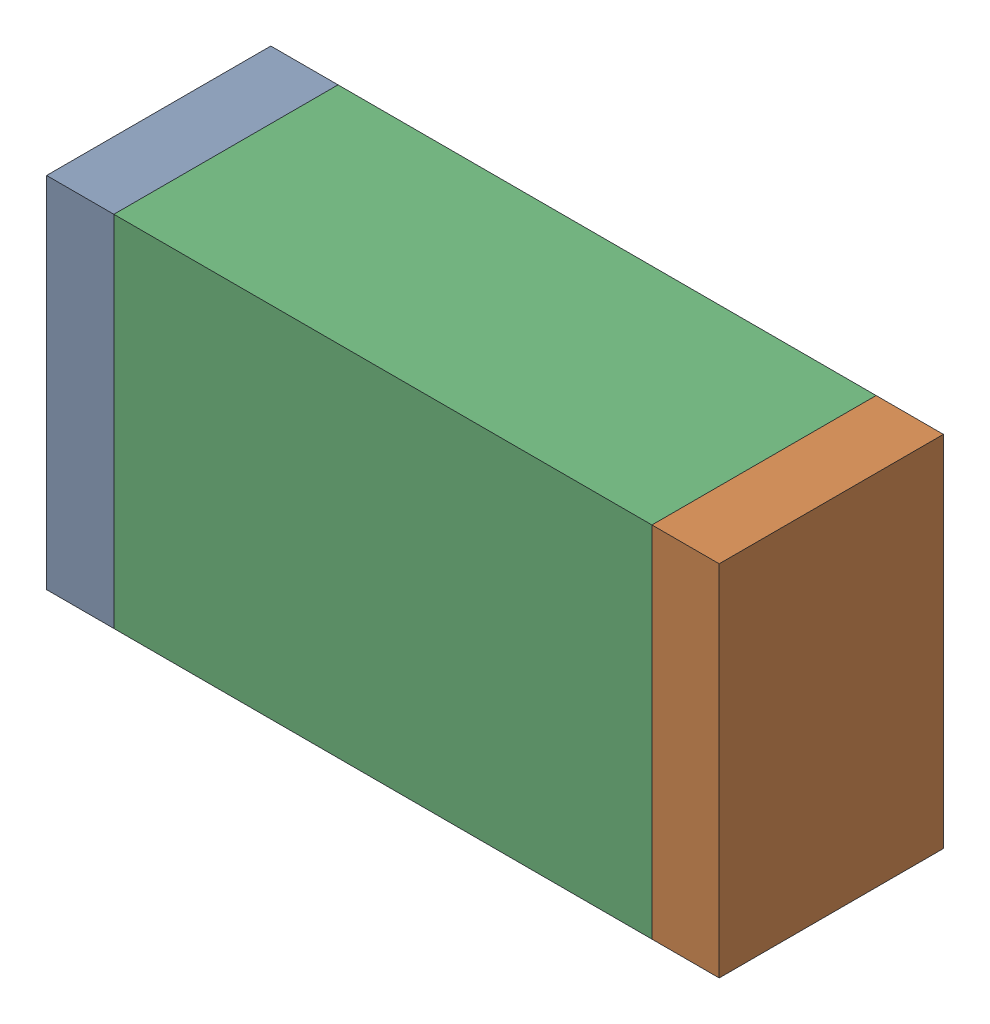
SolidWorks assembly R31, configuration Default. Lengths in mm.
Overall size (1.5 0.8 0.5).
6 component instances, 2 part files, 0 mates.
Components (placement in the parent):
- 836752496-1: 836752496 [Default] at (120.725 47.95 0) size (0.15 0.8 0.5)
  - Extruded_2-1: Extruded_2 [Default] at origin size (0.15 0.8 0.5)
- 836752496-2: 836752496 [Default] at (122.075 47.95 0) size (0.15 0.8 0.5)
  - Extruded_2-1: Extruded_2 [Default] at origin size (0.15 0.8 0.5)
- 836752368-1: 836752368 [Default] at (121.4 47.95 0) size (1.2 0.8 0.5)
  - Extruded-1: Extruded [Default] at origin size (1.2 0.8 0.5)
